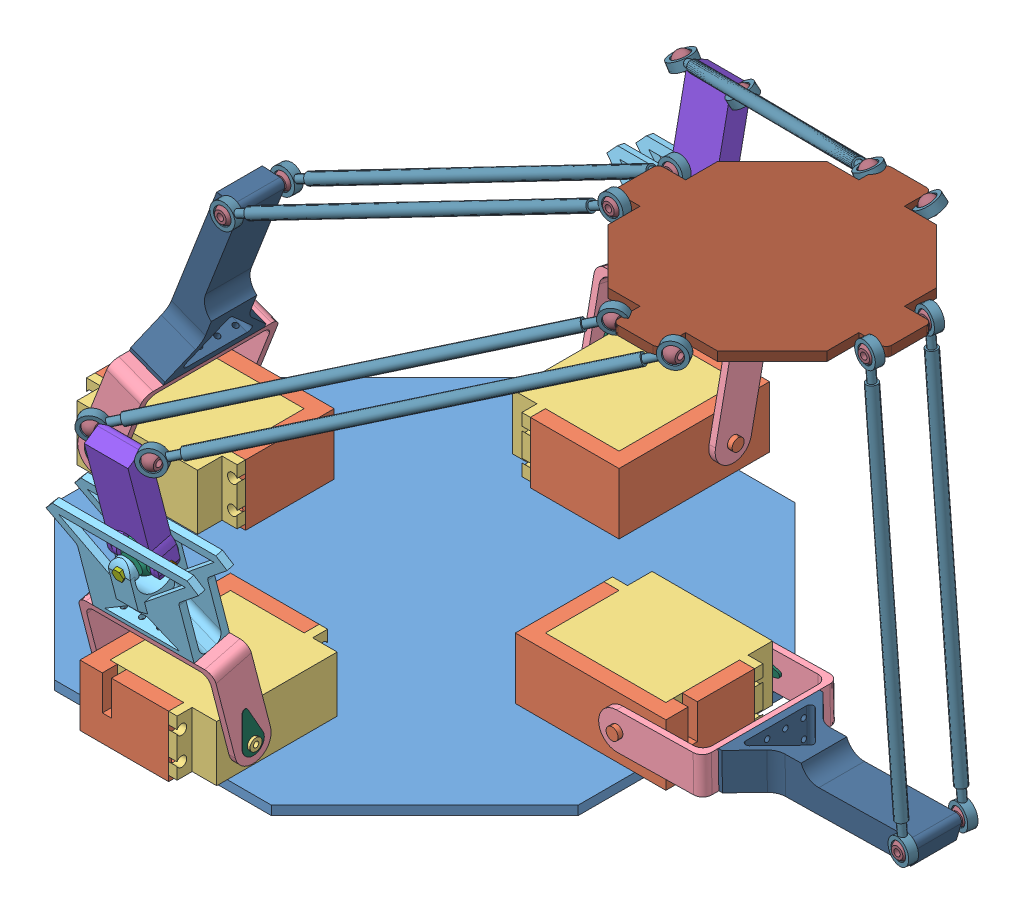
SolidWorks assembly asm, configuration 기본. Lengths in mm.
Overall size (442.61 260.89 352.48).
66 component instances, 15 part files, 155 mates.
Components (placement in the parent):
- delta_base_-1: delta_base_ [기본] at (16.2815 -22.3997 221) size (287.2 5 287.2)
- servobracket1_-1: servobracket1_ [기본] at (8418.954 -14.3997 21660.4366) x (0 0 -1) z (0 1 0) size (82.55 54.75 33.48)
- servobracket1_-2: servobracket1_ [기본] at (-21423.155 -14.3997 8623.6725) x (1 0 0) z (0 1 0) size (82.55 54.75 33.48)
- servobracket1_-3: servobracket1_ [기본] at (-8386.3909 -14.3997 -21218.4366) x (0 0 1) z (0 1 0) size (82.55 54.75 33.48)
- servobracket1_-4: servobracket1_ [기본] at (21455.7181 -14.3997 -8181.6725) x (-1 0 0) z (0 1 0) size (82.55 54.75 33.48)
- servo_drive_HV2060MG-1: servo_drive_HV2060MG [기본] at (-103.0792 0.8403 200.815) x (-1 0 0) z (0 0 1) size (82.55 30.48 64.98)
- servo_drive_HV2060MG-2: servo_drive_HV2060MG [기본] at (36.4665 0.8403 101.6393) x (0 0 -1) z (-1 0 0) size (82.55 30.48 64.98)
- servo_drive_HV2060MG-3: servo_drive_HV2060MG [기본] at (135.6423 0.8403 241.185) x (1 0 0) z (0 0 -1) size (82.55 30.48 64.98)
- servo_drive_HV2060MG-4: servo_drive_HV2060MG [기본] at (-3.9035 0.8403 340.3607) x (0 0 1) z (1 0 0) size (82.55 30.48 64.98)
- servobracket2_-1: servobracket2_ [기본] at (20.8415 46.331 370.0962) x (1 0 0) z (0 0.251391 -0.967886) size (75 57 20)
- servobracket2_-2: servobracket2_ [기본] at (11.7215 46.9006 74.3673) x (-1 0 0) z (0 0.198974 0.980005) size (75 57 20)
- univ_link1-1: univ_link1 [기본] at (14.8415 67.9062 375.7) x (0 -0.251391 0.967886) z (1 0 0) size (28.84 52.05 83.6)
- univ_link1-2: univ_link1 [기본] at (5.7215 68.7459 69.932) x (0 0.198974 0.980005) z (1 0 0) size (28.84 52.05 83.6)
- ball-1: ball [기본] at (20.8415 82.4293 379.4721) x (-1 0 0) z (0 0.251391 -0.967886) size (18 14 18)
- ball-2: ball [기본] at (11.7215 83.4509 66.9464) x (1 0 0) z (0 0.198974 0.980005) size (18 14 18)
- univ_bolt_-1: univ_bolt_ [기본] at (20.8415 86.2001 364.9541) x (1 0 0) z (0 -0.967886 -0.251391) size (6.46 12 5.59)
- univ_bolt_-2: univ_bolt_ [기본] at (11.7215 86.4356 81.6466) x (0.5 -0.848709 0.172317) z (0.866025 0.490002 -0.099487) size (6.46 12 5.59)
- univ_bolt_-3: univ_bolt_ [기본] at (20.8415 78.6584 393.9906) x (1 0 0) z (0 0.967886 0.251391) size (6.46 12 5.59)
- univ_bolt_-4: univ_bolt_ [기본] at (11.7215 80.4664 52.2465) x (0.5 0.848709 -0.172317) z (0.866025 -0.490002 0.099487) size (6.46 12 5.59)
- univ_link2-3: univ_link2 [기본] at (11.733 99.3355 69.8437) x (-1 0 0) z (0 -0.198974 -0.980005) size (28.56 68.77 12)
- univ_bolt2_-1: univ_bolt2_ [기본] at (26.7328 83.4509 66.9464) x (0 0.198974 0.980005) z (0 -0.980005 0.198974) size (6.46 12 5.59)
- univ_bolt2_-2: univ_bolt2_ [기본] at (-3.2672 83.4509 66.9464) x (0 -0.198974 -0.980005) z (0 -0.980005 0.198974) size (6.46 12 5.59)
- univ_link2-4: univ_link2 [기본] at (20.8526 98.4467 377.4333) x (1 0 0) z (0 -0.251391 0.967886) size (28.56 68.77 12)
- univ_bolt2_-3: univ_bolt2_ [기본] at (5.8528 82.4293 379.4721) x (0 0.251391 -0.967886) z (0 -0.967886 -0.251391) size (6.46 12 5.59)
- univ_bolt2_-4: univ_bolt2_ [기본] at (35.8528 82.4293 379.4721) x (0 -0.251391 0.967886) z (0 -0.967886 -0.251391) size (6.46 12 5.59)
- servobracket2_-3: servobracket2_ [기본] at (-103.9958 44.6568 225.56) x (0 0 1) z (0.932264 -0.361778 0) size (75 57 20)
- servobracket2_-4: servobracket2_ [기본] at (200.5555 1.6477 216.44) x (0 0 -1) z (-0.017178 0.999852 0) size (75 57 20)
- link1_-1: link1_ [기본] at (200.3837 11.6463 244.19) x (0 0 -1) z (-0.999852 -0.017178 0) size (55.5 20 93)
- link1_-2: link1_ [기본] at (-94.6731 41.039 197.81) x (0 0 1) z (-0.361778 -0.932264 0) size (55.5 20 93)
- delta_end_-1: delta_end_ [기본] at (201.6406 231.8041 215.8126) x (-1 0 0) z (0 0 1) size (150 5 150)
- link_bridge_-1: link_bridge_ [기본] at (290.5444 3.1938 216.4377) x (-1 0 0) z (0 1 0) size (4.5 28.5 4.5)
- bearing-1: bearing [기본] at (290.5444 3.1938 200.0127) x (0 1 0) z (1 0 0) size (9.35 6.85 9.35)
- link_bridge_-2: link_bridge_ [기본] at (271.6406 229.3041 215.8126) x (0.013819 0.999905 0) z (0.999905 -0.013819 0) size (4.5 28.5 4.5)
- bearing-2: bearing [기본] at (271.6406 229.3041 199.3876) x (0.999983 -0.005841 0) z (-0.005841 -0.999983 0) size (9.35 6.85 9.35)
- bearing-3: bearing [기본] at (290.5444 3.1938 232.8627) x (1 0 0) z (0 -1 0) size (9.35 6.85 9.35)
- bearing-4: bearing [기본] at (271.6406 229.3041 232.2376) x (0 -1 0) z (1 0 0) size (9.35 6.85 9.35)
- rod-1: rod [기본] at (290.5444 3.1938 232.8627) x (-0.985926 -0.082829 -0.145219) z (-0.083313 0.99652 -0.002755) size (13.45 6 240.35)
- rod-2: rod [기본] at (271.6406 229.3041 199.3876) x (0.978488 0.082329 0.189164) z (0.083313 -0.99652 0.002755) size (13.45 6 240.35)
- link_bridge_-3: link_bridge_ [기본] at (131.6406 229.3041 215.8126) x (0.064888 0.997893 0) z (0.997893 -0.064888 0) size (4.5 28.5 4.5)
- bearing-5: bearing [기본] at (131.6406 229.3041 232.2376) x (-0.114329 0.993443 0) z (-0.993443 -0.114329 0) size (9.35 6.85 9.35)
- bearing-6: bearing [기본] at (131.6406 229.3041 199.3876) x (1 0 0) z (0 -1 0) size (9.35 6.85 9.35)
- link_bridge_-4: link_bridge_ [기본] at (-71.435 128.5626 225.5623) x (1 0 0) z (0 -1 0) size (4.5 28.5 4.5)
- bearing-7: bearing [기본] at (-71.435 128.5626 209.1373) x (1 0 0) z (0 -1 0) size (9.35 6.85 9.35)
- bearing-8: bearing [기본] at (-71.435 128.5626 241.9873) x (-1 0 0) z (0 -1 0) size (9.35 6.85 9.35)
- rod-3: rod [기본] at (131.6406 229.3041 199.3876) x (0.445728 -0.893909 0.047471) z (-0.895 -0.443991 0.042969) size (13.45 6 240.35)
- rod-4: rod [기본] at (-71.435 128.5626 241.9873) x (-0.445 0.895364 -0.01727) z (0.895 0.443991 -0.042969) size (13.45 6 240.35)
- link_bridge_-5: link_bridge_ [기본] at (201.6406 229.3041 145.8126) x (0 1 0) z (0 0 1) size (4.5 28.5 4.5)
- link_bridge_-6: link_bridge_ [기본] at (11.2274 142.6182 57.9946) x (0 0.98781 0.155666) z (0 0.155666 -0.98781) size (4.5 28.5 4.5)
- bearing-9: bearing [기본] at (185.2156 229.3041 145.8126) x (0 -0.010598 -0.999944) z (0 -0.999944 0.010598) size (9.35 6.85 9.35)
- bearing-10: bearing [기본] at (218.0656 229.3041 145.8126) x (0 0.847153 0.531349) z (0 -0.531349 0.847153) size (9.35 6.85 9.35)
- bearing-11: bearing [기본] at (-5.1976 142.6182 57.9946) x (0 -0.98781 -0.155666) z (0 -0.155666 0.98781) size (9.35 6.85 9.35)
- bearing-12: bearing [기본] at (27.6524 142.6182 57.9946) x (0 0.98781 0.155666) z (0 -0.155666 0.98781) size (9.35 6.85 9.35)
- rod-5: rod [기본] at (185.2156 229.3041 145.8126) x (0.317413 0.233792 -0.919016) z (-0.839194 -0.382044 -0.387034) size (13.45 6 240.35)
- rod-6: rod [기본] at (27.6524 142.6182 57.9946) x (-0.233534 -0.38956 0.890901) z (0.839194 0.382044 0.387034) size (13.45 6 240.35)
- link_bridge_-8: link_bridge_ [기본] at (21.3582 141.0296 391.593) x (0 0.999214 0.039639) z (0 -0.039639 0.999214) size (4.5 28.5 4.5)
- bearing-13: bearing [기본] at (37.7832 141.0296 391.593) x (0 0.967665 0.25224) z (0 -0.25224 0.967665) size (9.35 6.85 9.35)
- bearing-15: bearing [기본] at (4.9332 141.0296 391.593) x (0 -0.999213 -0.039671) z (0 -0.039671 0.999213) size (9.35 6.85 9.35)
- rod-8: rod [기본] at (37.7832 141.0296 391.593) x (-0.353566 0.92062 0.165678) z (0.794545 0.389046 -0.466198) size (13.45 6 240.35)
- rod-9: rod [기본] at (4.9332 141.0296 391.593) x (-0.290034 0.917693 0.271515) z (0.794545 0.389046 -0.466198) size (13.45 6 240.35)
- servobracket3_-2: servobracket3_ [기본] at (153.5748 0.8403 177.7076) x (-0.017178 0.999852 0) z (0.999852 0.017178 0) size (12 5 24.89)
- servobracket3_-3: servobracket3_ [기본] at (54.5739 0.8403 358.2932) x (0 -0.251391 0.967886) z (0 0.967886 0.251391) size (12 5 24.89)
- servobracket3_-4: servobracket3_ [기본] at (-22.0109 0.8403 83.7068) x (0 -0.198974 -0.980005) z (0 0.980005 -0.198974) size (12 5 24.89)
- servobracket3_-5: servobracket3_ [기본] at (-121.0117 0.8403 259.2924) x (-0.932264 0.361778 0) z (0.361778 0.932264 0) size (12 5 24.89)
- link_bridge_-9: link_bridge_ [기본] at (201.6406 229.3041 285.8126) x (0 1 0) z (0 0 -1) size (4.5 28.5 4.5)
- bearing-17: bearing [기본] at (218.0656 229.3041 285.8126) x (0 0.970974 0.239183) z (0 0.239183 -0.970974) size (9.35 6.85 9.35)
- bearing-18: bearing [기본] at (185.2156 229.3041 285.8126) x (0 0.908606 0.417655) z (0 -0.417655 0.908606) size (9.35 6.85 9.35)
Mates (geometry in assembly coordinates):
- 동심1: concentric anti-aligned: cylinder of delta_base_-1 through (11.2815 -17.3997 82.46) axis (0 -1 0) radius 1.5; cylinder of servobracket1_-1 through (11.2815 -17.3997 82.46) axis (0 1 0) radius 1.5
- 동심2: concentric anti-aligned: cylinder of delta_base_-1 through (21.2815 -17.3997 92.46) axis (0 -1 0) radius 1.5; cylinder of servobracket1_-1 through (21.2815 -17.3997 92.46) axis (0 1 0) radius 1.5
- 일치1: coincident anti-aligned: plane of delta_base_-1 through (16.2815 -17.3997 221) normal (0 1 0); plane of servobracket1_-1 through (8418.954 -17.3997 21660.4366) normal (0 -1 0)
- 동심3: concentric anti-aligned: cylinder of delta_base_-1 through (154.8215 -17.3997 216) axis (0 -1 0) radius 1.5; cylinder of servobracket1_-2 through (154.8215 -17.3997 216) axis (0 1 0) radius 1.5
- 동심4: concentric anti-aligned: cylinder of delta_base_-1 through (144.8215 -17.3997 226) axis (0 -1 0) radius 1.5; cylinder of servobracket1_-2 through (144.8215 -17.3997 226) axis (0 1 0) radius 1.5
- 일치4: coincident anti-aligned: plane of delta_base_-1 through (16.2815 -17.3997 221) normal (0 1 0); plane of servobracket1_-2 through (-21423.155 -17.3997 8623.6725) normal (0 -1 0)
- 동심5: concentric anti-aligned: cylinder of delta_base_-1 through (21.2815 -17.3997 359.54) axis (0 -1 0) radius 1.5; cylinder of servobracket1_-3 through (21.2815 -17.3997 359.54) axis (0 1 0) radius 1.5
- 동심6: concentric anti-aligned: cylinder of delta_base_-1 through (11.2815 -17.3997 349.54) axis (0 -1 0) radius 1.5; cylinder of servobracket1_-3 through (11.2815 -17.3997 349.54) axis (0 1 0) radius 1.5
- 일치5: coincident anti-aligned: plane of delta_base_-1 through (16.2815 -17.3997 221) normal (0 1 0); plane of servobracket1_-3 through (-8386.3909 -17.3997 -21218.4366) normal (0 -1 0)
- 동심7: concentric anti-aligned: cylinder of delta_base_-1 through (-122.2585 -17.3997 226) axis (0 -1 0) radius 1.5; cylinder of servobracket1_-4 through (-122.2585 -17.3997 226) axis (0 1 0) radius 1.5
- 동심8: concentric anti-aligned: cylinder of delta_base_-1 through (-112.2585 -17.3997 216) axis (0 -1 0) radius 1.5; cylinder of servobracket1_-4 through (-112.2585 -17.3997 216) axis (0 1 0) radius 1.5
- 일치6: coincident anti-aligned: plane of delta_base_-1 through (16.2815 -17.3997 221) normal (0 1 0); plane of servobracket1_-4 through (21455.7181 -17.3997 -8181.6725) normal (0 -1 0)
- 일치7: coincident anti-aligned: plane of servobracket1_-4 through (-70.0592 16.0803 241.1804) normal (-1 0 0); plane of servo_drive_HV2060MG-1 through (-70.0592 16.0803 241.1904) normal (1 0 0)
- 일치8: coincident anti-aligned: plane of servobracket1_-4 through (-70.0592 16.0803 200.815) normal (0 0 1); plane of servo_drive_HV2060MG-1 through (-103.0792 0.8403 200.815) normal (0 0 -1)
- 일치9: coincident anti-aligned: plane of servobracket1_-4 through (21455.7181 -14.3997 -8181.6725) normal (0 1 0); plane of servo_drive_HV2060MG-1 through (-136.0992 -14.3997 241.1904) normal (0 -1 0)
- 일치10: coincident anti-aligned: plane of servobracket1_-1 through (-3.8989 16.0803 134.6593) normal (0 0 -1); plane of servo_drive_HV2060MG-2 through (-3.9089 16.0803 134.6593) normal (0 0 1)
- 일치11: coincident anti-aligned: plane of servobracket1_-1 through (36.4665 16.0803 134.6593) normal (-1 0 0); plane of servo_drive_HV2060MG-2 through (36.4665 0.8403 101.6393) normal (1 0 0)
- 일치12: coincident anti-aligned: plane of servobracket1_-1 through (8418.954 -14.3997 21660.4366) normal (0 1 0); plane of servo_drive_HV2060MG-2 through (-3.9089 -14.3997 68.6193) normal (0 -1 0)
- 일치13: coincident anti-aligned: plane of servobracket1_-2 through (102.6223 16.0803 200.8196) normal (1 0 0); plane of servo_drive_HV2060MG-3 through (102.6223 16.0803 200.8096) normal (-1 0 0)
- 일치14: coincident anti-aligned: plane of servobracket1_-2 through (102.6223 16.0803 241.185) normal (0 0 -1); plane of servo_drive_HV2060MG-3 through (135.6423 0.8403 241.185) normal (0 0 1)
- 일치15: coincident anti-aligned: plane of servobracket1_-2 through (-21423.155 -14.3997 8623.6725) normal (0 1 0); plane of servo_drive_HV2060MG-3 through (168.6623 -14.3997 200.8096) normal (0 -1 0)
- 일치16: coincident anti-aligned: plane of servobracket1_-3 through (36.4619 16.0803 307.3407) normal (0 0 1); plane of servo_drive_HV2060MG-4 through (36.4719 16.0803 307.3407) normal (0 0 -1)
- 일치17: coincident anti-aligned: plane of servobracket1_-3 through (-3.9035 16.0803 307.3407) normal (1 0 0); plane of servo_drive_HV2060MG-4 through (-3.9035 0.8403 340.3607) normal (-1 0 0)
- 일치18: coincident anti-aligned: plane of servobracket1_-3 through (-8386.3909 -14.3997 -21218.4366) normal (0 1 0); plane of servo_drive_HV2060MG-4 through (36.4719 -14.3997 373.3807) normal (0 -1 0)
- 동심12: concentric aligned: circle of servobracket1_-3; cylinder of servobracket2_-1 through (-12.1585 0.8403 358.2809) axis (-1 0 0) radius 3.3
- 일치19: coincident anti-aligned: plane of servobracket1_-3 through (-12.1585 16.0803 381.6357) normal (-1 0 0); plane of servobracket2_-1 through (-12.1585 -11.3524 365.4458) normal (1 0 0)
- 동심13: concentric aligned: circle of servobracket1_-1; cylinder of servobracket2_-2 through (44.7215 0.8403 83.7191) axis (1 0 0) radius 3.3
- 일치20: coincident anti-aligned: plane of servobracket1_-1 through (44.7215 16.0803 60.3643) normal (1 0 0); plane of servobracket2_-2 through (44.7215 -10.9494 75.9088) normal (-1 0 0)
- 동심14: concentric anti-aligned: cylinder of servobracket2_-1 through (15.8415 43.1382 374.4329) axis (0 0.967886 0.251391) radius 1.5; cylinder of univ_link1-1 through (15.8415 47.9777 375.6898) axis (0 -0.967886 -0.251391) radius 1.5
- 동심15: concentric anti-aligned: cylinder of servobracket2_-1 through (25.8415 45.6522 364.754) axis (0 0.967886 0.251391) radius 1.5; cylinder of univ_link1-1 through (25.8415 50.4916 366.011) axis (0 -0.967886 -0.251391) radius 1.5
- 일치22: coincident anti-aligned: plane of servobracket2_-1 through (20.8415 46.331 370.0962) normal (0 0.967886 0.251391); plane of univ_link1-1 through (-6.9085 43.8171 379.7751) normal (0 -0.967886 -0.251391)
- 동심16: concentric anti-aligned: cylinder of servobracket2_-2 through (6.7215 45.9354 79.6653) axis (0 0.980005 -0.198974) radius 1.5; cylinder of univ_link1-2 through (6.7215 50.8355 78.6704) axis (0 -0.980005 0.198974) radius 1.5
- 동심17: concentric anti-aligned: cylinder of servobracket2_-2 through (16.7215 43.9457 69.8653) axis (0 0.980005 -0.198974) radius 1.5; cylinder of univ_link1-2 through (16.7215 48.8457 68.8704) axis (0 -0.980005 0.198974) radius 1.5
- 일치23: coincident anti-aligned: plane of servobracket2_-2 through (11.7215 46.9006 74.3673) normal (0 0.980005 -0.198974); plane of univ_link1-2 through (-16.0285 48.8903 84.1674) normal (0 -0.980005 0.198974)
- 일치24: coincident anti-aligned: circle of univ_link1-1; circle of ball-1
- 일치26: coincident anti-aligned: plane of univ_link1-1 through (22.4565 82.9899 366.1866) normal (0 0.967886 0.251391); plane of univ_bolt_-1 through (19.2265 82.9899 366.1866) normal (0 -0.967886 -0.251391)
- 동심18: concentric aligned: cylinder of ball-1 through (20.8415 80.6696 386.2473) axis (0 0.251391 -0.967886) radius 1.55; cylinder of univ_bolt_-1 through (20.8415 83.1835 376.5687) axis (0 0.251391 -0.967886) radius 1.55
- 일치27: coincident anti-aligned: plane of univ_link1-1 through (14.8415 71.1742 363.1177) normal (0 0.251391 -0.967886); plane of univ_bolt_-1 through (20.8415 85.6974 366.8898) normal (0 -0.251391 0.967886)
- 일치28: coincident anti-aligned: plane of univ_link1-2 through (10.1065 83.2963 80.2432) normal (0 0.980005 -0.198974); plane of univ_bolt_-2 through (13.3365 83.2963 80.2432) normal (0 -0.980005 0.198974)
- 동심19: concentric aligned: cylinder of ball-2 through (11.7215 82.0581 60.0863) axis (0 0.198974 0.980005) radius 1.55; cylinder of univ_bolt_-2 through (11.7215 84.0479 69.8866) axis (0 0.198974 0.980005) radius 1.55
- 일치29: coincident anti-aligned: plane of univ_link1-2 through (5.7215 71.3326 82.6722) normal (0 0.198974 0.980005); plane of univ_bolt_-2 through (11.7215 86.0376 79.6866) normal (0 -0.198974 -0.980005)
- 동심20: concentric anti-aligned: cylinder of ball-1 through (20.8415 80.6696 386.2473) axis (0 0.251391 -0.967886) radius 1.55; cylinder of univ_bolt_-3 through (20.8415 81.6751 382.376) axis (0 -0.251391 0.967886) radius 1.55
- 일치30: coincident anti-aligned: plane of univ_link1-1 through (19.2265 76.4538 391.3516) normal (0 0.967886 0.251391); plane of univ_bolt_-3 through (22.4565 76.4538 391.3516) normal (0 -0.967886 -0.251391)
- 일치31: coincident anti-aligned: plane of univ_link1-1 through (14.8415 64.638 388.2827) normal (0 -0.251391 0.967886); plane of univ_bolt_-3 through (20.8415 79.1612 392.0549) normal (0 0.251391 -0.967886)
- 일치32: coincident anti-aligned: plane of univ_link1-2 through (13.3365 78.123 54.7631) normal (0 0.980005 -0.198974); plane of univ_bolt_-4 through (10.1065 78.123 54.7631) normal (0 -0.980005 0.198974)
- 동심21: concentric anti-aligned: cylinder of ball-2 through (11.7215 82.0581 60.0863) axis (0 0.198974 0.980005) radius 1.55; cylinder of univ_bolt_-4 through (11.7215 82.854 64.0066) axis (0 -0.198974 -0.980005) radius 1.55
- 일치33: coincident anti-aligned: plane of univ_link1-2 through (5.7215 66.1593 57.1921) normal (0 -0.198974 -0.980005); plane of univ_bolt_-4 through (11.7215 80.8643 54.2065) normal (0 0.198974 0.980005)
- 일치35: coincident aligned: plane of ball-2 through (2.7215 84.6225 65.1779) normal (0 0.198974 0.980005); plane of univ_link2-3 through (26.1531 84.6198 65.1784) normal (0 0.198974 0.980005)
- 일치37: coincident anti-aligned: plane of univ_link2-3 through (24.7328 87.3861 72.2698) normal (0 -0.980005 0.198974); plane of univ_bolt2_-1 through (24.7328 86.5136 67.9725) normal (0 0.980005 -0.198974)
- 일치38: coincident anti-aligned: plane of ball-2 through (2.7215 84.6225 65.1779) normal (0 0.198974 0.980005); plane of univ_bolt2_-1 through (14.7328 84.6225 65.1779) normal (0 -0.198974 -0.980005)
- 일치39: coincident anti-aligned: plane of ball-2 through (2.7215 82.2794 68.7148) normal (0 0.980005 -0.198974); plane of univ_bolt2_-1 through (14.7328 81.6825 65.7748) normal (0 -0.980005 0.198974)
- 일치40: coincident anti-aligned: plane of univ_link2-3 through (24.7328 99.3355 69.8437) normal (1 0 0); plane of univ_bolt2_-1 through (24.7328 83.4509 66.9464) normal (-1 0 0)
- 일치126: coincident aligned: circle of univ_link1-2; circle of ball-2
- 일치44: coincident anti-aligned: plane of univ_link2-3 through (-1.2672 86.5139 67.974) normal (0 -0.980005 0.198974); plane of univ_bolt2_-2 through (-1.2672 85.8709 64.8071) normal (0 0.980005 -0.198974)
- 일치45: coincident anti-aligned: plane of ball-2 through (2.7215 85.2194 68.1179) normal (0 -0.198974 -0.980005); plane of univ_bolt2_-2 through (8.7328 85.2194 68.1179) normal (0 0.198974 0.980005)
- 일치46: coincident anti-aligned: plane of ball-2 through (2.7215 82.2794 68.7148) normal (0 0.980005 -0.198974); plane of univ_bolt2_-2 through (8.7328 82.2794 68.7148) normal (0 -0.980005 0.198974)
- 일치47: coincident anti-aligned: plane of univ_link2-3 through (-1.2672 99.3355 69.8437) normal (-1 0 0); plane of univ_bolt2_-2 through (-1.2672 83.4509 66.9464) normal (1 0 0)
- 일치49: coincident aligned: plane of ball-1 through (29.8415 83.5041 381.3011) normal (0 0.251391 -0.967886); plane of univ_link2-4 through (6.4325 83.5014 381.3004) normal (0 0.251391 -0.967886)
- 일치50: coincident anti-aligned: plane of univ_link2-4 through (7.8528 86.6451 374.368) normal (0 -0.967886 -0.251391); plane of univ_bolt2_-3 through (7.8528 85.5428 378.6122) normal (0 0.967886 0.251391)
- 일치51: coincident anti-aligned: plane of ball-1 through (29.8415 83.5041 381.3011) normal (0 0.251391 -0.967886); plane of univ_bolt2_-3 through (17.8528 83.5041 381.3011) normal (0 -0.251391 0.967886)
- 일치52: coincident anti-aligned: plane of ball-1 through (29.8415 81.3546 377.6432) normal (0 0.967886 0.251391); plane of univ_bolt2_-3 through (17.8528 80.6004 380.5469) normal (0 -0.967886 -0.251391)
- 일치53: coincident anti-aligned: plane of univ_link2-4 through (7.8528 98.4467 377.4333) normal (-1 0 0); plane of univ_bolt2_-3 through (7.8528 82.4293 379.4721) normal (1 0 0)
- 일치54: coincident anti-aligned: plane of univ_link2-4 through (33.8528 85.5432 378.6107) normal (0 -0.967886 -0.251391); plane of univ_bolt2_-4 through (33.8528 84.7308 381.7385) normal (0 0.967886 0.251391)
- 일치55: coincident anti-aligned: plane of ball-1 through (29.8415 84.2582 378.3974) normal (0 -0.251391 0.967886); plane of univ_bolt2_-4 through (23.8528 84.2582 378.3974) normal (0 0.251391 -0.967886)
- 일치56: coincident anti-aligned: plane of ball-1 through (29.8415 81.3546 377.6432) normal (0 0.967886 0.251391); plane of univ_bolt2_-4 through (23.8528 81.3546 377.6432) normal (0 -0.967886 -0.251391)
- 일치57: coincident anti-aligned: plane of univ_link2-4 through (33.8528 98.4467 377.4333) normal (1 0 0); plane of univ_bolt2_-4 through (33.8528 82.4293 379.4721) normal (-1 0 0)
- 동심22: concentric aligned: circle of servobracket1_-4; cylinder of servobracket2_-3 through (-120.9993 0.8403 192.56) axis (0 0 -1) radius 3.3
- 일치58: coincident anti-aligned: plane of servobracket1_-4 through (-144.3542 16.0803 192.56) normal (0 0 -1); plane of servobracket2_-3 through (-133.9398 -4.8645 192.56) normal (0 0 1)
- 동심23: concentric aligned: circle of servobracket1_-2; cylinder of servobracket2_-4 through (153.5624 0.8403 249.44) axis (0 0 1) radius 3.3
- 일치59: coincident anti-aligned: plane of servobracket1_-2 through (176.9173 16.0803 249.44) normal (0 0 1); plane of servobracket2_-4 through (143.7357 -9.33 249.44) normal (0 0 -1)
- 동심24: concentric anti-aligned: cylinder of servobracket2_-4 through (198.6417 -3.3859 221.44) axis (0.999852 0.017178 0) radius 1.5; cylinder of link1_-1 through (205.6406 -3.2656 221.44) axis (-0.999852 -0.017178 0) radius 1.5
- 동심25: concentric anti-aligned: cylinder of servobracket2_-4 through (198.4699 6.6126 211.44) axis (0.999852 0.017178 0) radius 1.5; cylinder of link1_-1 through (205.4689 6.7329 211.44) axis (-0.999852 -0.017178 0) radius 1.5
- 일치60: coincident anti-aligned: plane of servobracket2_-4 through (200.5555 1.6477 216.44) normal (0.999852 0.017178 0); plane of link1_-1 through (200.7273 -8.3508 188.69) normal (-0.999852 -0.017178 0)
- 동심26: concentric anti-aligned: cylinder of servobracket2_-3 through (-109.3807 44.6011 230.56) axis (0.361778 0.932264 0) radius 1.5; cylinder of link1_-2 through (-106.8482 51.127 230.56) axis (-0.361778 -0.932264 0) radius 1.5
- 동심27: concentric anti-aligned: cylinder of servobracket2_-3 through (-100.058 40.9834 220.56) axis (0.361778 0.932264 0) radius 1.5; cylinder of link1_-2 through (-97.5256 47.5092 220.56) axis (-0.361778 -0.932264 0) radius 1.5
- 일치61: coincident anti-aligned: plane of servobracket2_-3 through (-103.9958 44.6568 225.56) normal (0.361778 0.932264 0); plane of link1_-2 through (-113.3184 48.2745 253.31) normal (-0.361778 -0.932264 0)
- 동심29: concentric anti-aligned: cylinder of link1_-1 through (290.5444 3.1938 188.69) axis (0 0 1) radius 2.15; cylinder of link_bridge_-1 through (290.5444 3.1938 228.9377) axis (0 0 -1) radius 2
- 일치66: coincident anti-aligned: plane of link1_-1 through (290.714 -6.8048 228.9377) normal (0 0 1); plane of link_bridge_-1 through (290.5444 3.1938 228.9377) normal (0 0 -1)
- 일치68: coincident anti-aligned: plane of link_bridge_-1 through (290.5444 3.1938 203.4377) normal (0 0 -1); plane of bearing-1 through (290.5444 3.1938 203.4377) normal (0 0 1)
- 동심30: concentric aligned: cylinder of link_bridge_-1 through (290.5444 3.1938 202.1877) axis (0 0 1) radius 1.775; cylinder of bearing-1 through (290.5444 3.1938 196.5877) axis (0 0 1) radius 1.775
- 동심31: concentric anti-aligned: cylinder of delta_end_-1 through (271.6406 229.3041 140.8126) axis (0 0 1) radius 2; cylinder of link_bridge_-2 through (271.6406 229.3041 228.3126) axis (0 0 -1) radius 2
- 일치70: coincident anti-aligned: plane of delta_end_-1 through (201.6406 226.8041 228.3126) normal (0 0 1); plane of link_bridge_-2 through (271.6406 229.3041 228.3126) normal (0 0 -1)
- 동심32: concentric aligned: cylinder of link_bridge_-2 through (271.6406 229.3041 201.5626) axis (0 0 1) radius 1.775; cylinder of bearing-2 through (271.6406 229.3041 195.9626) axis (0 0 1) radius 1.775
- 일치71: coincident anti-aligned: plane of link_bridge_-2 through (271.6406 229.3041 202.8126) normal (0 0 -1); plane of bearing-2 through (271.6406 229.3041 202.8126) normal (0 0 1)
- 동심35: concentric anti-aligned: cylinder of link_bridge_-1 through (290.5444 3.1938 230.6877) axis (0 0 -1) radius 1.775; cylinder of bearing-3 through (290.5444 3.1938 229.4377) axis (0 0 1) radius 1.775
- 일치76: coincident anti-aligned: plane of link_bridge_-1 through (290.5444 3.1938 229.4377) normal (0 0 1); plane of bearing-3 through (290.5444 3.1938 229.4377) normal (0 0 -1)
- 일치78: coincident anti-aligned: plane of link_bridge_-2 through (271.6406 229.3041 228.8126) normal (0 0 1); plane of bearing-4 through (271.6406 229.3041 228.8126) normal (0 0 -1)
- 동심36: concentric aligned: cylinder of link_bridge_-2 through (271.6406 229.3041 230.0626) axis (0 0 -1) radius 1.775; cylinder of bearing-4 through (271.6406 229.3041 235.6626) axis (0 0 -1) radius 1.775
- 일치79: coincident: sphere of bearing-3; circle of rod-1
- 일치80: coincident: sphere of bearing-4; circle of rod-1
- 일치81: coincident: sphere of bearing-1; circle of rod-2
- 일치82: coincident: sphere of bearing-2; circle of rod-2
- 동심37: concentric anti-aligned: cylinder of delta_end_-1 through (131.6406 229.3041 140.8126) axis (0 0 1) radius 2; cylinder of link_bridge_-3 through (131.6406 229.3041 228.3126) axis (0 0 -1) radius 2
- 일치83: coincident anti-aligned: plane of delta_end_-1 through (201.6406 226.8041 203.3126) normal (0 0 -1); plane of link_bridge_-3 through (131.6406 229.3041 203.3126) normal (0 0 1)
- 동심38: concentric aligned: cylinder of link_bridge_-3 through (131.6406 229.3041 230.0626) axis (0 0 -1) radius 1.775; cylinder of bearing-5 through (131.6406 229.3041 235.6626) axis (0 0 -1) radius 1.775
- 일치84: coincident anti-aligned: plane of link_bridge_-3 through (131.6406 229.3041 228.8126) normal (0 0 1); plane of bearing-5 through (131.6406 229.3041 228.8126) normal (0 0 -1)
- 동심39: concentric aligned: cylinder of link_bridge_-3 through (131.6406 229.3041 201.5626) axis (0 0 1) radius 1.775; cylinder of bearing-6 through (131.6406 229.3041 195.9626) axis (0 0 1) radius 1.775
- 일치85: coincident anti-aligned: plane of link_bridge_-3 through (131.6406 229.3041 202.8126) normal (0 0 -1); plane of bearing-6 through (131.6406 229.3041 202.8126) normal (0 0 1)
- 동심40: concentric aligned: cylinder of link1_-2 through (-71.435 128.5626 253.31) axis (0 0 -1) radius 2.15; cylinder of link_bridge_-4 through (-71.435 128.5626 238.0623) axis (0 0 -1) radius 2
- 일치86: coincident anti-aligned: plane of link1_-2 through (-80.7584 132.1783 213.0623) normal (0 0 -1); plane of link_bridge_-4 through (-71.435 128.5626 213.0623) normal (0 0 1)
- 동심41: concentric aligned: cylinder of link_bridge_-4 through (-71.435 128.5626 211.3123) axis (0 0 1) radius 1.775; cylinder of bearing-7 through (-71.435 128.5626 205.7123) axis (0 0 1) radius 1.775
- 일치87: coincident anti-aligned: plane of link_bridge_-4 through (-71.435 128.5626 212.5623) normal (0 0 -1); plane of bearing-7 through (-71.435 128.5626 212.5623) normal (0 0 1)
- 동심42: concentric aligned: cylinder of link_bridge_-4 through (-71.435 128.5626 239.8123) axis (0 0 -1) radius 1.775; cylinder of bearing-8 through (-71.435 128.5626 245.4123) axis (0 0 -1) radius 1.775
- 일치88: coincident anti-aligned: plane of link_bridge_-4 through (-71.435 128.5626 238.5623) normal (0 0 1); plane of bearing-8 through (-71.435 128.5626 238.5623) normal (0 0 -1)
- 일치89: coincident: sphere of bearing-7; circle of rod-3
- 일치91: coincident: sphere of bearing-6; circle of rod-3
- 일치93: coincident: sphere of bearing-5; circle of rod-4
- 일치95: coincident: sphere of bearing-8; circle of rod-4
- 동심43: concentric aligned: cylinder of delta_end_-1 through (126.6406 229.3041 145.8126) axis (1 0 0) radius 2; cylinder of link_bridge_-5 through (189.1406 229.3041 145.8126) axis (1 0 0) radius 2
- 일치96: coincident anti-aligned: plane of delta_end_-1 through (214.1406 226.8041 215.8126) normal (1 0 0); plane of link_bridge_-5 through (214.1406 229.3041 145.8126) normal (-1 0 0)
- 동심44: concentric aligned: cylinder of univ_link2-3 through (26.1531 142.6182 57.9946) axis (-1 0 0) radius 2; cylinder of link_bridge_-6 through (23.7274 142.6182 57.9946) axis (-1 0 0) radius 2
- 일치97: coincident anti-aligned: plane of univ_link2-3 through (23.7274 140.8275 49.1746) normal (1 0 0); plane of link_bridge_-6 through (23.7274 142.6182 57.9946) normal (-1 0 0)
- 동심45: concentric aligned: cylinder of link_bridge_-5 through (187.3906 229.3041 145.8126) axis (1 0 0) radius 1.775; cylinder of bearing-9 through (181.7906 229.3041 145.8126) axis (1 0 0) radius 1.775
- 일치98: coincident anti-aligned: plane of link_bridge_-5 through (188.6406 229.3041 145.8126) normal (-1 0 0); plane of bearing-9 through (188.6406 229.3041 145.8126) normal (1 0 0)
- 동심46: concentric aligned: cylinder of link_bridge_-5 through (215.8906 229.3041 145.8126) axis (-1 0 0) radius 1.775; cylinder of bearing-10 through (221.4906 229.3041 145.8126) axis (-1 0 0) radius 1.775
- 일치99: coincident anti-aligned: plane of link_bridge_-5 through (214.6406 229.3041 145.8126) normal (1 0 0); plane of bearing-10 through (214.6406 229.3041 145.8126) normal (-1 0 0)
- 동심47: concentric aligned: cylinder of link_bridge_-6 through (-3.0226 142.6182 57.9946) axis (1 0 0) radius 1.775; cylinder of bearing-11 through (-8.6226 142.6182 57.9946) axis (1 0 0) radius 1.775
- 일치100: coincident anti-aligned: plane of link_bridge_-6 through (-1.7726 142.6182 57.9946) normal (-1 0 0); plane of bearing-11 through (-1.7726 142.6182 57.9946) normal (1 0 0)
- 동심48: concentric aligned: cylinder of link_bridge_-6 through (25.4774 142.6182 57.9946) axis (-1 0 0) radius 1.775; cylinder of bearing-12 through (31.0774 142.6182 57.9946) axis (-1 0 0) radius 1.775
- 일치101: coincident anti-aligned: plane of link_bridge_-6 through (24.2274 142.6182 57.9946) normal (1 0 0); plane of bearing-12 through (24.2274 142.6182 57.9946) normal (-1 0 0)
- 일치102: coincident: sphere of bearing-11; circle of rod-5
- 일치103: coincident: sphere of bearing-9; circle of rod-5
- 일치104: coincident: sphere of bearing-12; circle of rod-6
- 일치107: coincident: sphere of bearing-10; circle of rod-6
- 동심50: concentric aligned: cylinder of univ_link2-4 through (6.4325 141.0296 391.593) axis (1 0 0) radius 2; cylinder of link_bridge_-8 through (8.8582 141.0296 391.593) axis (1 0 0) radius 2
- 일치111: coincident anti-aligned: plane of univ_link2-4 through (8.8582 138.7671 400.3039) normal (-1 0 0); plane of link_bridge_-8 through (8.8582 141.0296 391.593) normal (1 0 0)
- 동심51: concentric aligned: cylinder of link_bridge_-8 through (35.6082 141.0296 391.593) axis (-1 0 0) radius 1.775; cylinder of bearing-13 through (41.2082 141.0296 391.593) axis (-1 0 0) radius 1.775
- 일치112: coincident anti-aligned: plane of link_bridge_-8 through (34.3582 141.0296 391.593) normal (1 0 0); plane of bearing-13 through (34.3582 141.0296 391.593) normal (-1 0 0)
- 동심53: concentric aligned: cylinder of link_bridge_-8 through (7.1082 141.0296 391.593) axis (1 0 0) radius 1.775; cylinder of bearing-15 through (1.5082 141.0296 391.593) axis (1 0 0) radius 1.775
- 일치116: coincident anti-aligned: plane of link_bridge_-8 through (8.3582 141.0296 391.593) normal (-1 0 0); plane of bearing-15 through (8.3582 141.0296 391.593) normal (1 0 0)
- 일치117: coincident: sphere of bearing-13; circle of rod-8
- 일치120: coincident: sphere of bearing-15; circle of rod-9
- 탄젠트2: tangent: circle of ball-1; plane of univ_link2-4 through (11.5915 77.4069 384.3667) normal (1 0 0)
- 동심56: concentric anti-aligned: cylinder of servo_drive_HV2060MG-3 through (153.5748 0.8403 176.2076) axis (0 0 1) radius 3.302; cylinder of servobracket3_-2 through (153.5748 0.8403 182.7076) axis (0 0 -1) radius 3.3
- 일치123: coincident anti-aligned: plane of servo_drive_HV2060MG-3 through (135.6423 0.8403 182.7076) normal (0 0 -1); plane of servobracket3_-2 through (153.5748 0.8403 182.7076) normal (0 0 1)
- 평행1: parallel anti-aligned: plane of servobracket2_-4 through (198.8579 7.5739 181.44) normal (-0.275374 0.961337 0); plane of servobracket3_-2 through (155.227 -4.9277 182.7076) normal (0.275374 -0.961337 0)
- 동심57: concentric aligned: cylinder of servo_drive_HV2060MG-4 through (61.0739 0.8403 358.2932) axis (-1 0 0) radius 3.302; cylinder of servobracket3_-3 through (59.5739 0.8403 358.2932) axis (-1 0 0) radius 3.3
- 일치127: coincident anti-aligned: plane of servo_drive_HV2060MG-4 through (54.5739 0.8403 340.3607) normal (1 0 0); plane of servobracket3_-3 through (54.5739 0.8403 358.2932) normal (-1 0 0)
- 평행2: parallel anti-aligned: plane of servobracket2_-1 through (55.8415 46.2836 363.9319) normal (0 -0.007682 -0.99997); plane of servobracket3_-3 through (59.5739 0.8864 364.2931) normal (0 0.007682 0.99997)
- 동심58: concentric aligned: cylinder of servo_drive_HV2060MG-2 through (-28.5109 0.8403 83.7068) axis (1 0 0) radius 3.302; cylinder of servobracket3_-4 through (-27.0109 0.8403 83.7068) axis (1 0 0) radius 3.3
- 일치129: coincident anti-aligned: plane of servo_drive_HV2060MG-2 through (-22.0109 0.8403 101.6393) normal (-1 0 0); plane of servobracket3_-4 through (-22.0109 0.8403 83.7068) normal (1 0 0)
- 평행3: parallel anti-aligned: plane of servobracket2_-2 through (-23.2785 46.5218 80.5202) normal (0 -0.06145 0.99811); plane of servobracket3_-4 through (-27.0109 1.209 77.7181) normal (0 0.06145 -0.99811)
- 동심59: concentric aligned: cylinder of servo_drive_HV2060MG-1 through (-121.0117 0.8403 265.7924) axis (0 0 -1) radius 3.302; cylinder of servobracket3_-5 through (-121.0117 0.8403 264.2924) axis (0 0 -1) radius 3.3
- 일치131: coincident anti-aligned: plane of servo_drive_HV2060MG-1 through (-103.0792 0.8403 259.2924) normal (0 0 1); plane of servobracket3_-5 through (-121.0117 0.8403 259.2924) normal (0 0 -1)
- 평행4: parallel anti-aligned: plane of servobracket2_-3 through (-99.0219 41.0152 260.56) normal (0.806863 -0.590738 0); plane of servobracket3_-5 through (-125.8529 4.3848 264.2924) normal (-0.806863 0.590738 0)
- 동심60: concentric anti-aligned: cylinder of delta_end_-1 through (126.6406 229.3041 285.8126) axis (1 0 0) radius 2; cylinder of link_bridge_-9 through (214.1406 229.3041 285.8126) axis (-1 0 0) radius 2
- 일치132: coincident anti-aligned: plane of delta_end_-1 through (189.1406 226.8041 215.8126) normal (-1 0 0); plane of link_bridge_-9 through (189.1406 229.3041 285.8126) normal (1 0 0)
- 동심61: concentric anti-aligned: cylinder of link_bridge_-9 through (215.8906 229.3041 285.8126) axis (-1 0 0) radius 1.775; cylinder of bearing-17 through (214.6406 229.3041 285.8126) axis (1 0 0) radius 1.775
- 일치133: coincident anti-aligned: plane of link_bridge_-9 through (214.6406 229.3041 285.8126) normal (1 0 0); plane of bearing-17 through (214.6406 229.3041 285.8126) normal (-1 0 0)
- 동심62: concentric anti-aligned: cylinder of link_bridge_-9 through (187.3906 229.3041 285.8126) axis (1 0 0) radius 1.775; cylinder of bearing-18 through (188.6406 229.3041 285.8126) axis (-1 0 0) radius 1.775
- 일치134: coincident anti-aligned: plane of link_bridge_-9 through (188.6406 229.3041 285.8126) normal (-1 0 0); plane of bearing-18 through (188.6406 229.3041 285.8126) normal (1 0 0)
- 일치136: coincident: circle of rod-8; sphere of bearing-17
- 일치137: coincident: circle of rod-9; sphere of bearing-18
- 탄젠트5: tangent: circle of ball-2; plane of univ_link2-3 through (2.4715 78.699 61.7888) normal (1 0 0)
- 평행5: parallel anti-aligned: plane of delta_base_-1 through (16.2815 -17.3997 221) normal (0 1 0); plane of delta_end_-1 through (201.6406 226.8041 215.8126) normal (0 -1 0)
